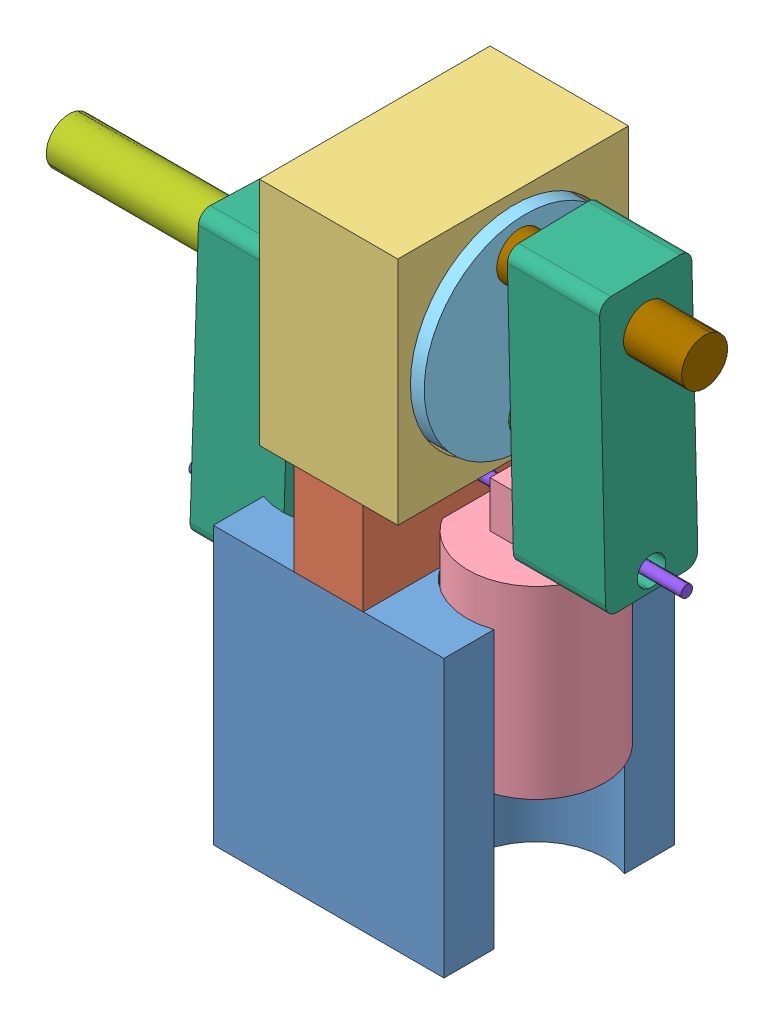
SolidWorks assembly final, configuration Default. Lengths in mm.
Overall size (356.51 333.23 127).
13 component instances, 10 part files, 29 mates.
Components (placement in the parent):
- Part1a-1: Part1a [Default] at (-13.4564 107.9025 38.062) size (127 152.4 127)
- Part1b-1: Part1b [Default] at (30.9936 260.3025 38.062) size (38.1 50.8 127)
- Part1^final-1: Part1^final [Default] at origin (virtual)
- Part1c-1: Part1c [Default] at (11.9436 311.1025 38.062) size (76.2 127 127)
- Part5and6-1: Part5and6 [Default] at (100.8436 181.4265 -25.438) x (0 0 1) z (-1 0 0) size (74.93 127 74.93)
- Part5and6-4: Part5and6 [Default] at (-0.7564 105.5404 -25.438) x (0 0 -1) z (1 0 0) size (74.93 127 74.93)
- Part3final-1: Part3final [Default] at (5.5936 374.8302 -25.9965) x (0 0.996291 0.08605) z (0 0.08605 -0.996291) size (111.76 88.9 111.76)
- Partalmost-1: Partalmost [Default] at (-64.2564 363.0902 -4.7209) x (0 -0.999463 0.032768) z (0 0.032768 0.999463) size (152.4 50.8 50.8)
- newbigsil-1: newbigsil [Default] at (94.4936 336.8715 -29.275) x (0 0.092557 0.995707) z (0 -0.995707 0.092557) size (25.4 254.66 25.4)
- newsmallsil-1: newsmallsil [Default] at (183.7757 295.7265 -25.438) x (0 0.696322 -0.71773) z (0 0.71773 0.696322) size (6.35 127 6.35)
- finalbigsil-1: finalbigsil [Default] at (196.3499 412.7889 -22.718) x (0 -0.966197 -0.257807) z (0 0.257807 -0.966197) size (25.4 177.8 25.4)
- newsmallsil-2: newsmallsil [Default] at (-87.2988 219.8404 -25.438) x (0 -1 0) z (0 0 1) size (6.35 127 6.35)
- Partalmost-4: Partalmost [Default] at (113.5436 437.592 3.2652) x (0 -0.99973 -0.02323) z (0 -0.02323 0.99973) size (152.4 50.8 50.8)
Mates (geometry in assembly coordinates):
- Coincident2: coincident: plane of Part1a-1 through (-13.4564 260.3025 38.062) normal (0 1 0); plane of Part1b-1 through (30.9936 260.3025 38.062) normal (0 -1 0)
- Parallel2: parallel: plane of Part1a-1 through (-13.4564 260.3025 38.062) normal (0 1 0); plane of Part1b-1 through (30.9936 311.1025 38.062) normal (0 1 0)
- Coincident8: coincident: plane of Part1a-1 through (-13.4564 260.3025 38.062) normal (0 0 1); line of Part1b-1 through (30.9936 260.3025 38.062) axis (1 0 0)
- Distance3: distance = 44.45 mm: point of Part1b-1; point of Part1a-1
- Coincident13: coincident: line of Part1b-1 through (30.9936 311.1025 38.062) axis (1 0 0); line of Part1c-1 through (11.9436 311.1025 38.062) axis (1 0 0)
- Distance5: distance = 19.05 mm: point of Part1c-1; point of Part1b-1
- Coincident15: coincident: line of Part1b-1 through (30.9936 311.1025 -88.938) axis (1 0 0); line of Part1c-1 through (11.9436 311.1025 -88.938) axis (1 0 0)
- Parallel16: parallel: plane of Part5and6-1 through (113.5436 308.4265 -12.738) normal (1 0 0); line of assembly
- Concentric11: concentric: cylinder of Part1a-1 through (100.8436 260.3025 -25.438) axis (0 -1 0) radius 38.1; cylinder of Part5and6-1 through (100.8436 283.0265 -25.438) axis (0 -1 0) radius 37.465
- Concentric12: concentric: cylinder of Part1a-1 through (-0.7564 260.3025 -25.438) axis (0 -1 0) radius 38.1; cylinder of Part5and6-4 through (-0.7564 207.1404 -25.438) axis (0 -1 0) radius 37.465
- Parallel24: parallel: plane of Part1b-1 through (30.9936 311.1025 38.062) normal (-1 0 0); plane of Part5and6-4 through (-13.4564 232.5404 -38.138) normal (-1 0 0)
- Parallel25: parallel: plane of Part1b-1 through (69.0936 311.1025 38.062) normal (1 0 0); plane of Part5and6-1 through (113.5436 308.4265 -12.738) normal (1 0 0)
- Concentric14: concentric: cylinder of Part1c-1 through (88.1436 374.8302 -25.9965) axis (-1 0 0) radius 57.15; cylinder of Part3final-1 through (94.4936 374.8302 -25.9965) axis (-1 0 0) radius 55.88
- Distance32: distance = 6.35 mm: plane of Part3final-1 through (5.5936 374.8302 -25.9965) normal (-1 0 0); plane of Part1c-1 through (11.9436 438.1025 38.062) normal (-1 0 0)
- Parallel27: parallel: plane of Part1b-1 through (30.9936 311.1025 38.062) normal (-1 0 0); plane of Partalmost-1 through (-13.4564 216.9106 -6.2817) normal (1 0 0)
- Coincident78: coincident: line of Part5and6-4 through (-13.4564 232.5404 -12.738) axis (0 -1 0); plane of Partalmost-1 through (-13.4564 216.9106 -6.2817) normal (1 0 0)
- Concentric16: concentric: cylinder of Part3final-1 through (94.4936 336.8715 -29.275) axis (-1 0 0) radius 12.7; cylinder of newbigsil-1 through (-160.1629 336.8715 -29.275) axis (1 0 0) radius 12.7
- Concentric17: concentric: cylinder of Part5and6-1 through (227.8436 295.7265 -25.438) axis (-1 0 0) radius 3.175; cylinder of newsmallsil-1 through (56.7757 295.7265 -25.438) axis (1 0 0) radius 3.175
- Concentric19: concentric: cylinder of Part3final-1 through (94.4936 412.7889 -22.718) axis (-1 0 0) radius 12.7; cylinder of finalbigsil-1 through (18.5499 412.7889 -22.718) axis (1 0 0) radius 12.7
- Concentric22: concentric: cylinder of Partalmost-1 through (-13.4564 336.8715 -29.275) axis (-1 0 0) radius 12.7; cylinder of newbigsil-1 through (-160.1629 336.8715 -29.275) axis (1 0 0) radius 12.7
- Concentric23: concentric: cylinder of Part3final-1 through (94.4936 336.8715 -29.275) axis (-1 0 0) radius 12.7; cylinder of newbigsil-1 through (-160.1629 336.8715 -29.275) axis (1 0 0) radius 12.7
- Concentric26: concentric: circle of Partalmost-1; cylinder of newsmallsil-2 through (39.7012 219.8404 -25.438) axis (-1 0 0) radius 3.175
- Concentric27: concentric: cylinder of Part5and6-4 through (-127.7564 219.8404 -25.438) axis (1 0 0) radius 3.175; cylinder of newsmallsil-2 through (39.7012 219.8404 -25.438) axis (-1 0 0) radius 3.175
- Coincident93: coincident: circle of Part3final-1; cylinder of newbigsil-1 through (-160.1629 336.8715 -29.275) axis (1 0 0) radius 12.7
- Concentric28: concentric: cylinder of finalbigsil-1 through (18.5499 412.7889 -22.718) axis (1 0 0) radius 12.7; cylinder of Partalmost-4 through (164.3436 412.7889 -22.718) axis (-1 0 0) radius 12.7
- Concentric29: concentric: cylinder of newsmallsil-1 through (56.7757 295.7265 -25.438) axis (1 0 0) radius 3.175; cylinder of Partalmost-4 through (164.3436 295.7265 -25.438) axis (-1 0 0) radius 7.8595
- Coincident103: coincident: plane of Part3final-1 through (94.4936 374.8302 -25.9965) normal (1 0 0); plane of newbigsil-1 through (94.4936 336.8715 -29.275) normal (1 0 0)
- Distance43: distance = 32.0063 mm: plane of finalbigsil-1 through (196.3499 412.7889 -22.718) normal (1 0 0); plane of Partalmost-4 through (164.3436 291.7289 -6.4758) normal (1 0 0)
- Coincident111: coincident: plane of Part5and6-1 through (113.5436 308.4265 -12.738) normal (1 0 0); plane of Partalmost-4 through (113.5436 291.7289 -6.4758) normal (-1 0 0)
